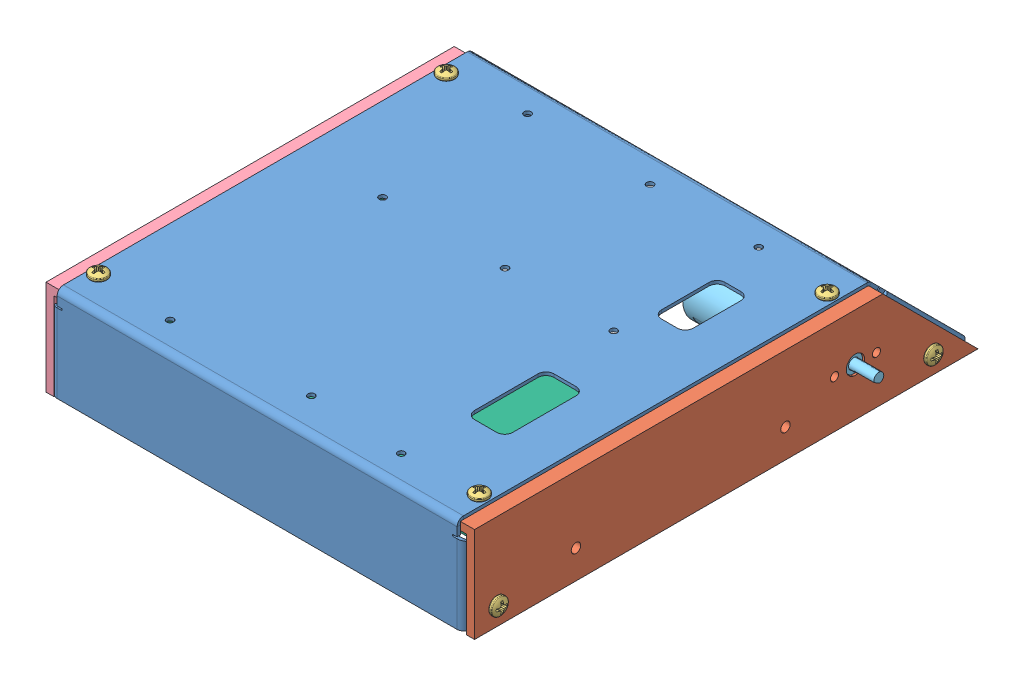
SolidWorks assembly Assem1, configuration Default. Lengths in mm.
Overall size (190.1 58.33 202.7).
28 component instances, 9 part files, 54 mates.
Components (placement in the parent):
- Steel-1: Steel [Default] at (90.7433 78.2691 11.0735) size (165.11 38.1 202.31)
- AngleAlum-1: AngleAlum [Default] at (93.9183 98.5978 73.779) x (1 0 0) z (0 1 0) size (19.69 201.42 38.1)
- 91735A144-1: 91735A144 [91735A144] at (87.5683 68.1178 -109.101) x (0 -1 0) z (1 0 0) size (6.86 6.86 8.86)
- 91735A144-2: 91735A144 [91735A144] at (-68.0067 93.5178 62.349) x (1 0 0) z (0 1 0) size (6.86 6.86 8.86)
- 91735A144-3: 91735A144 [91735A144] at (84.3933 93.5178 -76.8249) x (1 0 0) z (0 1 0) size (6.86 6.86 8.86)
- AngleAlum2-1: AngleAlum2 [Default] at (-77.5317 98.5978 73.779) x (0 1 0) z (-1 0 0) size (38.1 201.42 19.69)
- 91735A144-5: 91735A144 [91735A144] at (84.3933 93.5178 62.349) x (1 0 0) z (0 1 0) size (6.86 6.86 8.86)
- 91735A144-6: 91735A144 [91735A144] at (-71.1817 68.1178 64.889) x (0 1 0) z (-1 0 0) size (6.86 6.86 8.86)
- 91735A144-7: 91735A144 [91735A144] at (-68.0067 93.5178 -76.8249) x (1 0 0) z (0 1 0) size (6.86 6.86 8.86)
- 91735A144-8: 91735A144 [91735A144] at (-71.1817 68.1178 -109.101) x (0 1 0) z (-1 0 0) size (6.86 6.86 8.86)
- 91735A144-9: 91735A144 [91735A144] at (87.5683 68.1178 64.889) x (0 -1 0) z (1 0 0) size (6.86 6.86 8.86)
- 25d-metal-gearmotor-75-99-1: 25d-metal-gearmotor-75-99 [Default] at (-55.9817 51.0124 -90.4106) x (0 0.924225 0.381849) z (-1 0 0) size (25 25 70.5)
- 25d-metal-gearmotor-75-99-2: 25d-metal-gearmotor-75-99 [Default] at (72.3683 63.3794 -104.924) x (0 0.523673 0.851919) z (1 0 0) size (25 25 70.5)
- Motor_Control_Board-2: Motor_Control_Board [Default] at (156.1906 117.5592 109.3653) x (0.000065 0 -1) z (0 1 0) size (150.02 100.02 20.09) (hidden)
- 98952A113-1: 98952A113 [98952A113] at (-38.3064 105.9178 63.3527) x (0 -1 0) z (0.480217 0 0.877149) size (20.19 5.2 4.5) (hidden)
- 98952A113-2: 98952A113 [98952A113] at (16.1937 105.9178 61.3563) x (0 -1 0) z (0.969858 0 0.243669) size (20.19 5.2 4.5) (hidden)
- 98952A113-3: 98952A113 [98952A113] at (-38.301 105.9178 -21.6473) x (0 -1 0) z (0.969858 0 0.243669) size (20.19 5.2 4.5) (hidden)
- 98952A113-4: 98952A113 [98952A113] at (10.7028 105.9178 -79.6441) x (0 -1 0) z (0.969858 0 0.243669) size (20.19 5.2 4.5) (hidden)
- 98952A113-5: 98952A113 [98952A113] at (54.199 105.9178 -21.6413) x (0 -1 0) z (0.969858 0 0.243669) size (20.19 5.2 4.5) (hidden)
- 98952A113-6: 98952A113 [98952A113] at (-38.2972 105.9178 -79.6473) x (0 -1 0) z (0.969858 0 0.243669) size (20.19 5.2 4.5) (hidden)
- 98952A113-7: 98952A113 [98952A113] at (10.699 105.9178 -21.6441) x (0 -1 0) z (0.969858 0 0.243669) size (20.19 5.2 4.5) (hidden)
- 98952A113-8: 98952A113 [98952A113] at (54.1936 105.9178 63.3587) x (0 -1 0) z (0.969858 0 0.243669) size (20.19 5.2 4.5) (hidden)
- 98952A113-9: 98952A113 [98952A113] at (54.2028 105.9178 -79.6413) x (0 -1 0) z (0.969858 0 0.243669) size (20.19 5.2 4.5) (hidden)
- keystone-PN1047-1: keystone-PN1047 [Default] at (59.4767 60.4978 -8.626) x (0.999962 0 0.008727) z (-0.008727 0 0.999962) size (39.78 18.43 81.03) (hidden)
- keystone-PN1047-2: keystone-PN1047 [Default] at (19.1415 60.4978 -8.626) x (0.999962 0 0.008727) z (-0.008727 0 0.999962) size (39.78 18.43 81.03) (hidden)
- keystone-PN1047-3: keystone-PN1047 [Default] at (-21.1937 60.4978 -8.626) x (0.999962 0 0.008727) z (-0.008727 0 0.999962) size (39.78 18.43 81.03) (hidden)
- keystone-PN1047-4: keystone-PN1047 [Default] at (-61.5289 60.4978 -8.626) x (0.999962 0 0.008727) z (-0.008727 0 0.999962) size (39.78 18.43 81.03) (hidden)
- Battery Plate-1: Battery Plate [Default] at (-77.5317 60.4978 73.779) x (-1 0 0) z (0 -1 0) size (165.1 95.25 20.32)
Mates (geometry in assembly coordinates):
- Coincident13: coincident anti-aligned: plane of AngleAlum2-1 through (-77.5317 98.5978 -129.421) normal (-1 0 0); plane of 91735A144-6 through (-77.5317 68.1178 64.889) normal (1 0 0)
- Coincident15: coincident anti-aligned: plane of AngleAlum-1 through (93.9183 60.4978 -129.421) normal (1 0 0); plane of 91735A144-1 through (93.9183 68.1178 -109.101) normal (-1 0 0)
- Coincident16: coincident anti-aligned: plane of AngleAlum-1 through (93.9183 60.4978 -129.421) normal (1 0 0); plane of 91735A144-9 through (93.9183 68.1178 64.889) normal (-1 0 0)
- Coincident18: coincident anti-aligned: plane of AngleAlum2-1 through (-74.3567 60.4978 -129.421) normal (1 0 0); plane of 25d-metal-gearmotor-75-99-1 through (-74.3567 79.5478 -78.621) normal (-1 0 0)
- Coincident19: coincident anti-aligned: plane of AngleAlum-1 through (90.7433 95.4228 -129.421) normal (-1 0 0); plane of 25d-metal-gearmotor-75-99-2 through (90.7433 79.5478 -78.621) normal (1 0 0)
- Concentric1: concentric anti-aligned: circle of 25d-metal-gearmotor-75-99-1; circle of 25d-metal-gearmotor-75-99-2
- Concentric3: concentric anti-aligned: circle of AngleAlum-1; circle of 25d-metal-gearmotor-75-99-2
- Coincident35: coincident anti-aligned: plane of Steel-1 through (90.7433 98.5978 -152.4241) normal (1 0 0); plane of AngleAlum-1 through (90.7433 95.4228 -129.421) normal (-1 0 0)
- Coincident36: coincident anti-aligned: plane of Steel-1 through (-74.3567 98.5978 73.779) normal (0 -1 0); plane of AngleAlum-1 through (93.9183 98.5978 -129.421) normal (0 1 0)
- Coincident37: coincident anti-aligned: plane of Steel-1 through (-74.3567 98.5978 -152.4241) normal (-1 0 0); plane of AngleAlum2-1 through (-74.3567 60.4978 -129.421) normal (1 0 0)
- Coincident38: coincident anti-aligned: plane of Steel-1 through (-74.3567 98.5978 73.779) normal (0 -1 0); plane of AngleAlum2-1 through (-57.8467 98.5978 -129.421) normal (0 1 0)
- Coincident39: coincident anti-aligned: plane of Steel-1 through (-74.3567 61.7678 73.779) normal (0 0 -1); plane of AngleAlum2-1 through (-77.5317 98.5978 73.779) normal (0 0 1)
- Concentric4: concentric anti-aligned: circle of AngleAlum2-1; circle of 91735A144-6
- Concentric5: concentric anti-aligned: cylinder of AngleAlum-1 through (93.9183 68.1178 -109.101) axis (-1 0 0) radius 1.8986; circle of 91735A144-1
- Concentric6: concentric aligned: cylinder of Steel-1 through (89.4733 68.1178 64.889) axis (1 0 0) radius 1.7526; circle of 91735A144-9
- Parallel1: parallel anti-aligned: plane of Steel-1 through (-74.3567 99.8678 73.779) normal (0 1 0); plane of Motor_Control_Board-2 through (58.2028 115.8678 -79.641) normal (0 -1 0)
- Distance4: distance = 6.35 mm: plane of assembly through (0 0 -88.9989) normal (0 0 1); moEndPointRef_w of Motor_Control_Board-2
- Concentric7: concentric anti-aligned: circle of Steel-1; circle of 98952A113-1
- Coincident47: coincident anti-aligned: plane of Steel-1 through (-74.3567 99.8678 73.779) normal (0 1 0); plane of 98952A113-1 through (-36.0275 99.8678 62.1051) normal (0 -1 0)
- Concentric8: concentric anti-aligned: circle of Steel-1; circle of 98952A113-3
- Concentric9: concentric anti-aligned: circle of Steel-1; circle of 98952A113-6
- Concentric10: concentric anti-aligned: circle of Steel-1; circle of 98952A113-7
- Concentric11: concentric anti-aligned: circle of Steel-1; circle of 98952A113-2
- Concentric12: concentric anti-aligned: circle of Steel-1; circle of 98952A113-4
- Concentric13: concentric anti-aligned: circle of Steel-1; circle of 98952A113-8
- Concentric14: concentric anti-aligned: circle of Steel-1; circle of 98952A113-5
- Concentric15: concentric anti-aligned: circle of Steel-1; circle of 98952A113-9
- Coincident48: coincident anti-aligned: plane of Steel-1 through (-74.3567 99.8678 73.779) normal (0 1 0); plane of 98952A113-3 through (-37.6679 99.8678 -24.167) normal (0 -1 0)
- Coincident49: coincident anti-aligned: plane of Steel-1 through (-74.3567 99.8678 73.779) normal (0 1 0); plane of 98952A113-6 through (-37.6641 99.8678 -82.167) normal (0 -1 0)
- Coincident50: coincident anti-aligned: plane of Steel-1 through (-74.3567 99.8678 73.779) normal (0 1 0); plane of 98952A113-4 through (11.3359 99.8678 -82.1639) normal (0 -1 0)
- Coincident51: coincident anti-aligned: plane of Steel-1 through (-74.3567 99.8678 73.779) normal (0 1 0); plane of 98952A113-9 through (54.8359 99.8678 -82.161) normal (0 -1 0)
- Coincident52: coincident anti-aligned: plane of Steel-1 through (-74.3567 99.8678 73.779) normal (0 1 0); plane of 98952A113-5 through (54.8321 99.8678 -24.161) normal (0 -1 0)
- Coincident53: coincident anti-aligned: plane of Steel-1 through (-74.3567 99.8678 73.779) normal (0 1 0); plane of 98952A113-8 through (54.8266 99.8678 60.839) normal (0 -1 0)
- Coincident54: coincident anti-aligned: plane of Steel-1 through (-74.3567 99.8678 73.779) normal (0 1 0); plane of 98952A113-2 through (16.8267 99.8678 58.8365) normal (0 -1 0)
- Coincident55: coincident anti-aligned: plane of Steel-1 through (-74.3567 99.8678 73.779) normal (0 1 0); plane of 98952A113-7 through (11.3321 99.8678 -24.1639) normal (0 -1 0)
- Coincident56: coincident anti-aligned: plane of Motor_Control_Board-2 through (58.2028 115.8678 -79.641) normal (0 -1 0); plane of 98952A113-1 through (-36.0275 115.8678 62.1051) normal (0 1 0)
- Coincident57: coincident anti-aligned: plane of Steel-1 through (-74.3567 99.8678 73.779) normal (0 1 0); plane of 91735A144-5 through (84.3933 99.8678 62.349) normal (0 -1 0)
- Coincident58: coincident anti-aligned: plane of Steel-1 through (-74.3567 99.8678 73.779) normal (0 1 0); plane of 91735A144-3 through (84.3933 99.8678 -76.8249) normal (0 -1 0)
- Coincident59: coincident anti-aligned: plane of Steel-1 through (-74.3567 99.8678 73.779) normal (0 1 0); plane of 91735A144-2 through (-68.0067 99.8678 62.349) normal (0 -1 0)
- Concentric16: concentric anti-aligned: circle of AngleAlum2-1; circle of 91735A144-8
- Coincident61: coincident anti-aligned: plane of AngleAlum2-1 through (-77.5317 98.5978 -129.421) normal (-1 0 0); plane of 91735A144-8 through (-77.5317 68.1178 -109.101) normal (1 0 0)
- Coincident62: coincident anti-aligned: plane of Steel-1 through (-74.3567 99.8678 73.779) normal (0 1 0); plane of 91735A144-7 through (-68.0067 99.8678 -76.8249) normal (0 -1 0)
- InPlace1: in place: plane of ? through (-77.5317 46.0016 -129.421) normal (0 -1 0); plane of ? through (0 46.0016 0) normal (0 -1 0); moOrthogonalPlaneRef_w of ? through (-77.5317 46.0016 -129.421) normal (0 -1 0); unknown of ?; plane of ? through (-77.5317 46.0016 -129.421) normal (0 -1 0); line of ? through (-55 0 46.0016) axis (0 -1 0); plane of AngleAlum2-1 through (-77.5317 60.4978 -129.421) normal (0 -1 0); unknown of Battery Plate-1
- Coincident63: coincident aligned: plane of AngleAlum2-1; plane of Battery Plate-1
- Coincident64: coincident aligned: moOrthogonalPlaneRef_w of AngleAlum2-1 through (-77.5317 60.4978 73.779) normal (0 0 -1); plane of Battery Plate-1
- Coincident65: coincident anti-aligned: moOrthogonalPlaneRef_w of AngleAlum2-1 through (-77.5317 60.4978 73.779) normal (1 0 0); plane of Battery Plate-1
- Concentric17: concentric aligned: circle of keystone-PN1047-4; circle of Battery Plate-1
- Coincident67: coincident anti-aligned: plane of keystone-PN1047-4 through (-72.1542 60.4978 25.725) normal (0 -1 0); plane of Battery Plate-1 through (-77.5317 60.4978 73.779) normal (0 1 0)
- Concentric18: concentric aligned: circle of keystone-PN1047-3; circle of Battery Plate-1
- Coincident68: coincident anti-aligned: plane of keystone-PN1047-3 through (-31.819 60.4978 25.725) normal (0 -1 0); plane of Battery Plate-1 through (-77.5317 60.4978 73.779) normal (0 1 0)
- Concentric19: concentric aligned: circle of keystone-PN1047-2; circle of Battery Plate-1
- Coincident69: coincident anti-aligned: plane of keystone-PN1047-2 through (8.5162 60.4978 25.725) normal (0 -1 0); plane of Battery Plate-1 through (-77.5317 60.4978 73.779) normal (0 1 0)
- Concentric20: concentric aligned: circle of keystone-PN1047-1; circle of Battery Plate-1
- Coincident70: coincident anti-aligned: plane of keystone-PN1047-1 through (48.8514 60.4978 25.725) normal (0 -1 0); plane of Battery Plate-1 through (-77.5317 60.4978 73.779) normal (0 1 0)
